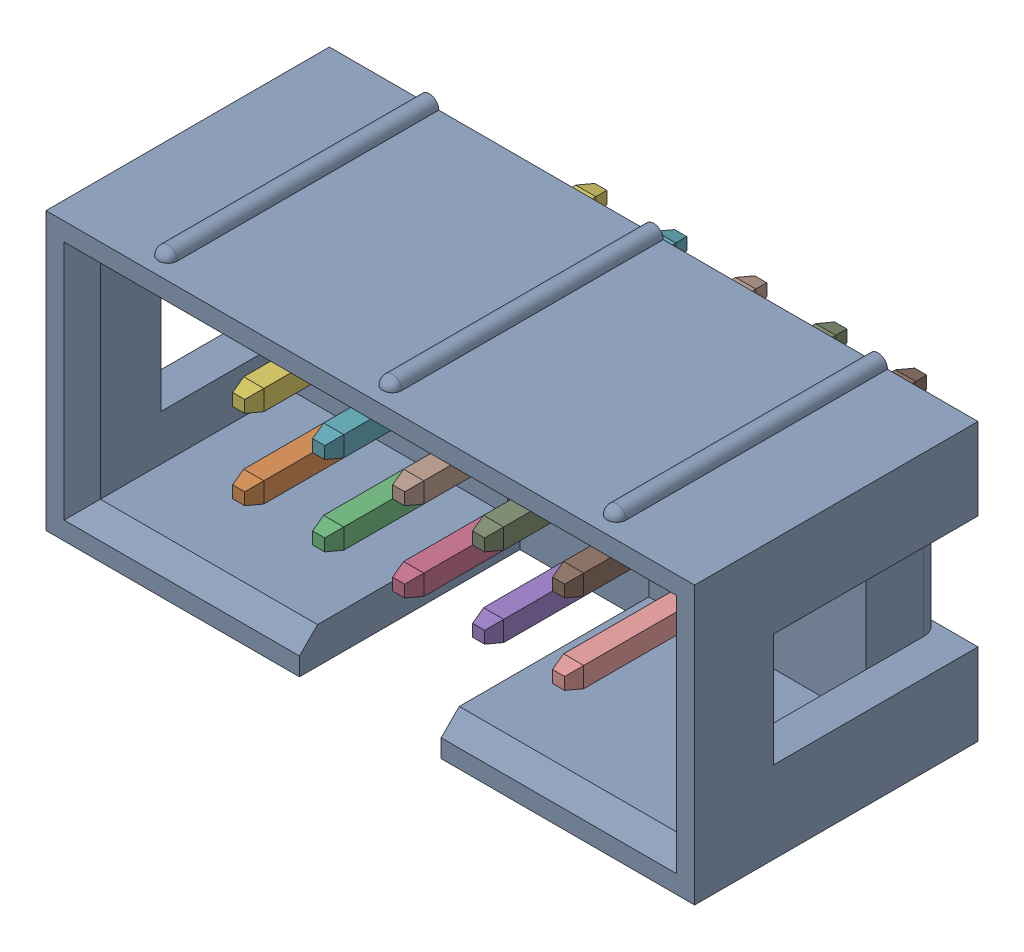
SolidWorks assembly DS1013-10SSiB v1, configuration DS1013-10SSiB v1. Lengths in mm.
Overall size (20.6 9.1 12.4).
11 component instances, 2 part files, 0 mates.
Components (placement in the parent):
- body-1: body [body] at origin size (20.6 9.1 9.3)
- pin-1: pin [pin] at origin size (0.64 0.64 11.5)
- pin-2: pin [pin] at (2.54 0 0) size (0.64 0.64 11.5)
- pin-3: pin [pin] at (5.08 0 0) size (0.64 0.64 11.5)
- pin-4: pin [pin] at (7.62 0 0) size (0.64 0.64 11.5)
- pin-5: pin [pin] at (0 2.54 0) size (0.64 0.64 11.5)
- pin-6: pin [pin] at (2.54 2.54 0) size (0.64 0.64 11.5)
- pin-7: pin [pin] at (5.08 2.54 0) size (0.64 0.64 11.5)
- pin-8: pin [pin] at (7.62 2.54 0) size (0.64 0.64 11.5)
- pin-9: pin [pin] at (10.16 0 0) size (0.64 0.64 11.5)
- pin-10: pin [pin] at (10.16 2.54 0) size (0.64 0.64 11.5)
